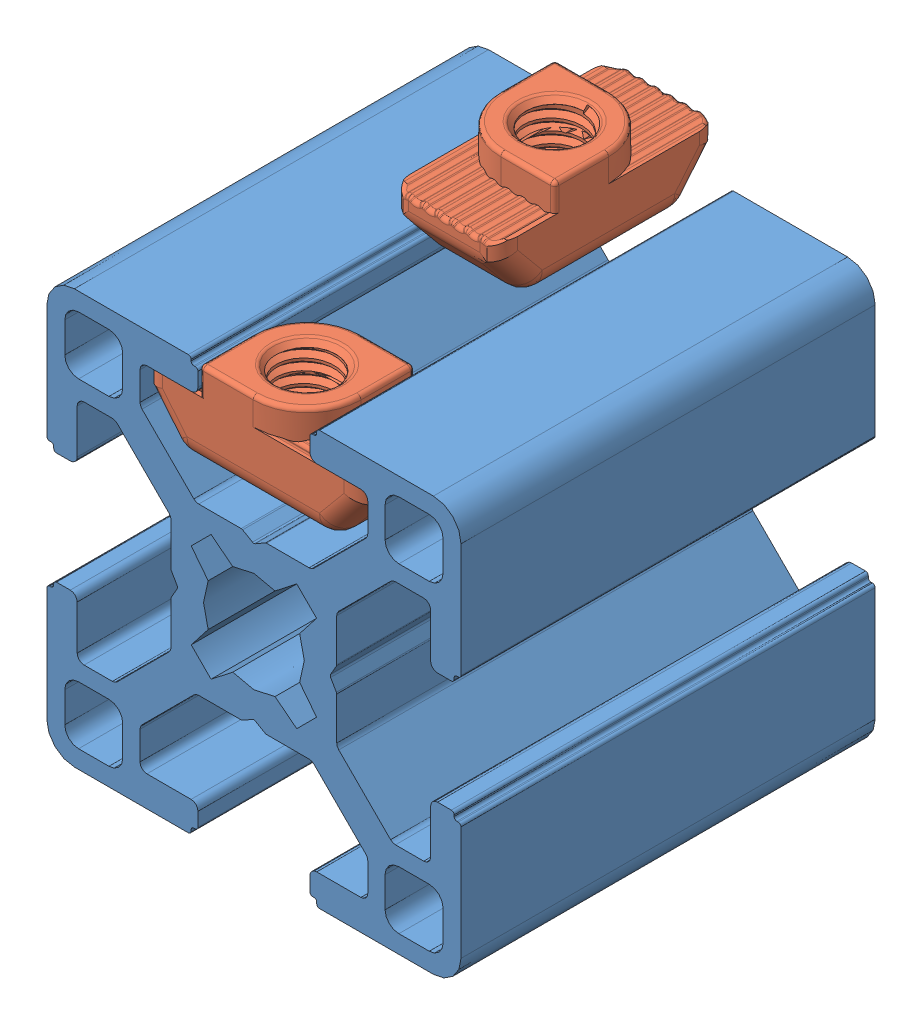
SolidWorks assembly Сборка Т-Гайка 8 паз, configuration По умолчанию. Lengths in mm.
Overall size (30 36.09 30).
3 component instances, 2 part files, 5 mates.
Components (placement in the parent):
- 30х30-1: 30х30 [По умолчанию] at origin size (30 30 30)
- Т-Гайка 8 паз-1: Т-Гайка 8 паз [По умолчанию] at (-0.05 8.3 26.1) size (16.08 6.51 7.8)
- Т-Гайка 8 паз-2: Т-Гайка 8 паз [По умолчанию] at (-0.05 14.5817 8.1643) x (0 0 -1) z (1 0 0) size (16.08 6.51 7.8)
Mates (geometry in assembly coordinates):
- Совпадение1: coincident anti-aligned: plane of 30х30-1 through (0 12.8 30) normal (0 -1 0); plane of Т-Гайка 8 паз-1 through (7.95 12.8 22.2) normal (0 1 0)
- Совпадение2: coincident aligned: plane of 30х30-1 through (0 0 30) normal (0 0 1); plane of Т-Гайка 8 паз-1 through (-0.05 8.3 30) normal (0 0 1)
- Совпадение3: coincident aligned: plane of Т-Гайка 8 паз-1 through (3.85 12.8 22.2) normal (1 0 0); plane of Т-Гайка 8 паз-2 through (3.85 14.5817 8.1643) normal (1 0 0)
- Параллельность1: parallel anti-aligned: plane of 30х30-1 through (0 15 30) normal (0 1 0); plane of Т-Гайка 8 паз-2 through (-3.95 14.5817 2.6643) normal (0 -1 0)
- Расстояние1: distance = 0.1 mm anti-aligned: plane of 30х30-1 through (-4.05 0 30) normal (1 0 0); plane of Т-Гайка 8 паз-1 through (-3.95 12.8 22.2) normal (-1 0 0)
